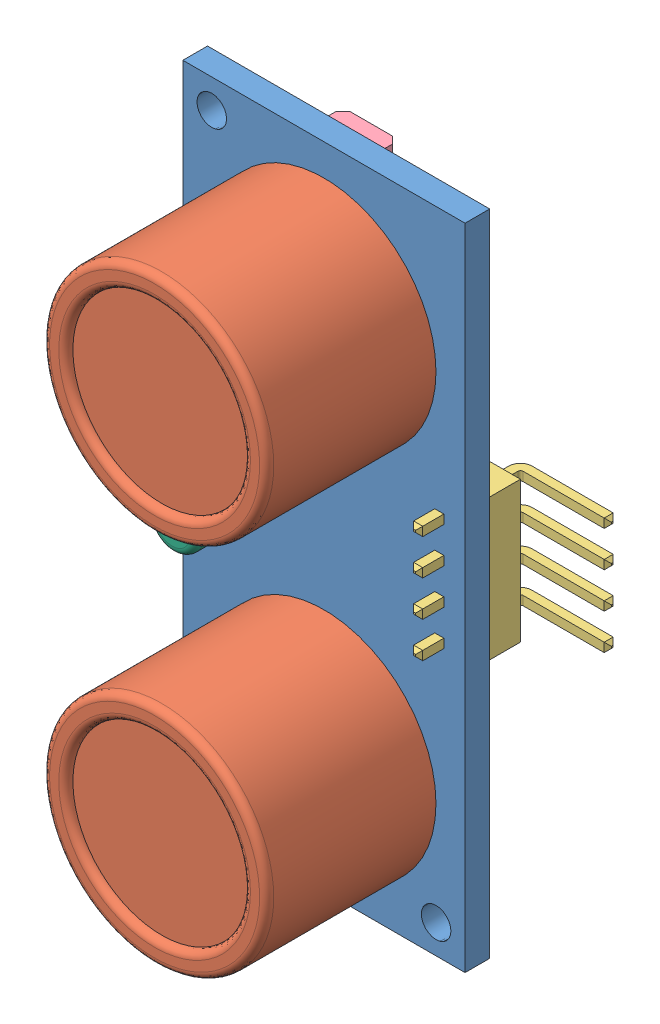
SolidWorks assembly HC-SR04 Ping Sensor, configuration Default. Lengths in mm.
Overall size (24.68 46 18.07).
14 component instances, 6 part files, 46 mates.
Components (placement in the parent):
- PCB-1: PCB [Default] at origin size (20 46 1.75)
- Transducer-1: Transducer [Default] at (0 -13.66 13.25) x (1 0 0) z (0 -1 0) size (15.88 12 15.88)
- Transducer-2: Transducer [Default] at (0 12.84 13.25) x (1 0 0) z (0 -1 0) size (15.88 12 15.88)
- 3 Pin Header 90 Degree-1: 3 Pin Header 90 Degree [Default] at (8.1775 0 -1.25) x (-1 0 0) z (0 -1 0) size (8 7.82 10)
- 14 Pin SMT-1: 14 Pin SMT [Default] at (-0.1 -19 -0.85) x (0 -1 0) z (1 0 0) size (6 1.6 8.8)
- 14 Pin SMT-2: 14 Pin SMT [Default] at (0 0.1174 -0.85) x (1 0 0) z (0 1 0) size (6 1.6 8.8)
- 14 Pin SMT-3: 14 Pin SMT [Default] at (0 18.0274 -0.85) x (1 0 0) z (0 1 0) size (6 1.6 8.8)
- Cap1 SMT-1: Cap1 SMT [Default] at (-1.505 7.9774 -0.9689) x (0 1 0) z (-1 0 0) size (4.5 1.84 1.75)
- Cap1 SMT-2: Cap1 SMT [Default] at (6.585 7.9774 -0.9689) x (0 1 0) z (-1 0 0) size (4.5 1.84 1.75)
- Cap1 SMT-3: Cap1 SMT [Default] at (-6.585 7.9774 -0.9689) x (0 1 0) z (-1 0 0) size (4.5 1.84 1.75)
- Cap1 SMT-4: Cap1 SMT [Default] at (4.045 7.9774 -0.9689) x (0 1 0) z (-1 0 0) size (4.5 1.84 1.75)
- Cap1 SMT-5: Cap1 SMT [Default] at (1.505 7.9774 -0.9689) x (0 1 0) z (-1 0 0) size (4.5 1.84 1.75)
- Cap1 SMT-6: Cap1 SMT [Default] at (-4.045 7.9774 -0.9689) x (0 1 0) z (-1 0 0) size (4.5 1.84 1.75)
- HC-SR04 Crystal-1: HC-SR04 Crystal [Default] at (-8.05 0 1.75) x (0 -1 0) z (0 0 1) size (10 3.5 2.7)
Mates (geometry in assembly coordinates):
- Coincident1: coincident anti-aligned: plane of PCB-1 through (-10 -23 1.75) normal (0 0 1); plane of Transducer-2 through (0 12.84 1.75) normal (0 0 -1)
- Coincident2: coincident anti-aligned: plane of PCB-1 through (-10 -23 1.75) normal (0 0 1); plane of Transducer-1 through (0 -13.66 1.75) normal (0 0 -1)
- Coincident3: coincident aligned: plane of PCB-1 through (0 0 0) normal (1 0 0); plane of Transducer-1
- Coincident4: coincident aligned: plane of PCB-1 through (0 0 0) normal (1 0 0); plane of Transducer-2
- Distance2: distance = 9.34 mm: plane of PCB-1 through (-10 -23 1.75) normal (0 -1 0); point of Transducer-1
- Distance3: distance = 10.16 mm: plane of PCB-1 through (-10 23 1.75) normal (0 1 0); point of Transducer-2
- Coincident8: coincident anti-aligned: plane of PCB-1 through (0 0 0) normal (0 1 0); plane of 3 Pin Header 90 Degree-1 through (8.1775 0 -1.25) normal (0 -1 0)
- Coincident9: coincident anti-aligned: plane of PCB-1 through (-10 -23 0) normal (0 0 -1); plane of 14 Pin SMT-1 through (-0.35 -22 0) normal (0 0 1)
- Coincident10: coincident anti-aligned: plane of PCB-1 through (-10 -23 0) normal (0 0 -1); plane of 14 Pin SMT-2 through (3 -0.1326 0) normal (0 0 1)
- Coincident11: coincident anti-aligned: plane of PCB-1 through (-10 -23 0) normal (0 0 -1); plane of 14 Pin SMT-3 through (3 19.0274 0) normal (0 0 1)
- Coincident13: coincident aligned: plane of PCB-1 through (0 0 0) normal (1 0 0); plane of 14 Pin SMT-2
- Coincident14: coincident aligned: plane of PCB-1 through (0 0 0) normal (1 0 0); plane of 14 Pin SMT-3
- Distance6: distance = 9.11 mm anti-aligned: plane of 14 Pin SMT-2 through (-2 4.5174 -1.6) normal (0 1 0); plane of 14 Pin SMT-3 through (-2 13.6274 -1.6) normal (0 -1 0)
- Coincident15: coincident anti-aligned: plane of PCB-1 through (-10 -23 0) normal (0 0 -1); plane of Cap1 SMT-1 through (-1.755 10.2274 0) normal (0 0 1)
- Coincident16: coincident anti-aligned: plane of PCB-1 through (-10 -23 0) normal (0 0 -1); plane of Cap1 SMT-2 through (6.335 10.2274 0) normal (0 0 1)
- Coincident17: coincident anti-aligned: plane of PCB-1 through (-10 -23 0) normal (0 0 -1); plane of Cap1 SMT-3 through (-6.835 10.2274 0) normal (0 0 1)
- Coincident18: coincident anti-aligned: plane of PCB-1 through (-10 -23 0) normal (0 0 -1); plane of Cap1 SMT-4 through (3.795 10.2274 0) normal (0 0 1)
- Coincident19: coincident anti-aligned: plane of PCB-1 through (-10 -23 0) normal (0 0 -1); plane of Cap1 SMT-5 through (1.255 10.2274 0) normal (0 0 1)
- Coincident20: coincident anti-aligned: plane of PCB-1 through (-10 -23 0) normal (0 0 -1); plane of Cap1 SMT-6 through (-4.295 10.2274 0) normal (0 0 1)
- Parallel1: parallel aligned: plane of Cap1 SMT-4 through (3.17 6.2274 -1.8439) normal (0 -1 0); plane of Cap1 SMT-5 through (0.63 6.2274 -1.8439) normal (0 -1 0)
- Parallel2: parallel aligned: plane of Cap1 SMT-2 through (5.71 6.2274 -1.8439) normal (0 -1 0); plane of Cap1 SMT-4 through (3.17 6.2274 -1.8439) normal (0 -1 0)
- Parallel3: parallel aligned: plane of PCB-1 through (-10 -23 1.75) normal (0 -1 0); plane of Cap1 SMT-2 through (5.71 6.2274 -1.8439) normal (0 -1 0)
- Distance7: distance = 0.79 mm anti-aligned: plane of Cap1 SMT-2 through (5.71 6.2274 -1.8439) normal (-1 0 0); plane of Cap1 SMT-4 through (4.92 6.2274 -1.8439) normal (1 0 0)
- Distance8: distance = 0.79 mm anti-aligned: plane of Cap1 SMT-4 through (3.17 6.2274 -1.8439) normal (-1 0 0); plane of Cap1 SMT-5 through (2.38 6.2274 -1.8439) normal (1 0 0)
- Distance9: distance = 2.54 mm aligned: plane of PCB-1 through (10 23 1.75) normal (1 0 0); plane of Cap1 SMT-2 through (7.46 6.2274 -1.8439) normal (1 0 0)
- Coincident21: coincident aligned: plane of Cap1 SMT-4 through (3.17 9.7274 -0.0939) normal (0 1 0); plane of Cap1 SMT-5 through (0.63 9.7274 -0.0939) normal (0 1 0)
- Coincident22: coincident aligned: plane of Cap1 SMT-2 through (5.71 9.7274 -0.0939) normal (0 1 0); plane of Cap1 SMT-4 through (3.17 9.7274 -0.0939) normal (0 1 0)
- Parallel4: parallel aligned: plane of Cap1 SMT-3 through (-7.46 6.2274 -1.8439) normal (0 -1 0); plane of Cap1 SMT-6 through (-4.92 6.2274 -1.8439) normal (0 -1 0)
- Parallel5: parallel aligned: plane of Cap1 SMT-1 through (-2.38 6.2274 -1.8439) normal (0 -1 0); plane of Cap1 SMT-6 through (-4.92 6.2274 -1.8439) normal (0 -1 0)
- Distance11: distance = 0.79 mm anti-aligned: plane of Cap1 SMT-1 through (-2.38 6.2274 -1.8439) normal (-1 0 0); plane of Cap1 SMT-6 through (-3.17 6.2274 -1.8439) normal (1 0 0)
- Distance12: distance = 0.79 mm anti-aligned: plane of Cap1 SMT-3 through (-5.71 6.2274 -1.8439) normal (1 0 0); plane of Cap1 SMT-6 through (-4.92 6.2274 -1.8439) normal (-1 0 0)
- Coincident23: coincident aligned: plane of Cap1 SMT-3 through (-7.46 9.7274 -0.0939) normal (0 1 0); plane of Cap1 SMT-6 through (-4.92 9.7274 -0.0939) normal (0 1 0)
- Coincident24: coincident aligned: plane of Cap1 SMT-1 through (-2.38 9.7274 -0.0939) normal (0 1 0); plane of Cap1 SMT-6 through (-4.92 9.7274 -0.0939) normal (0 1 0)
- Parallel6: parallel aligned: plane of PCB-1 through (-10 -23 1.75) normal (0 -1 0); plane of Cap1 SMT-3 through (-7.46 6.2274 -1.8439) normal (0 -1 0)
- Distance13: distance = 2.54 mm aligned: plane of PCB-1 through (-10 23 1.75) normal (-1 0 0); plane of Cap1 SMT-3 through (-7.46 6.2274 -1.8439) normal (-1 0 0)
- Coincident25: coincident aligned: plane of Cap1 SMT-1 through (-2.38 9.7274 -0.0939) normal (0 1 0); plane of Cap1 SMT-5 through (0.63 9.7274 -0.0939) normal (0 1 0)
- Distance15: distance = 1.71 mm anti-aligned: plane of 14 Pin SMT-2 through (-2 4.5174 -1.6) normal (0 1 0); plane of Cap1 SMT-5 through (0.63 6.2274 -1.8439) normal (0 -1 0)
- Coincident26: coincident anti-aligned: plane of PCB-1 through (-10 -23 0) normal (0 0 -1); plane of 3 Pin Header 90 Degree-1 through (9.6775 -5 0) normal (0 0 1)
- Distance16: distance = 1.5 mm aligned: plane of 3 Pin Header 90 Degree-1 through (8.5 4.4 -2.5) normal (1 0 0); plane of PCB-1 through (10 23 1.75) normal (1 0 0)
- Parallel7: parallel anti-aligned: plane of PCB-1 through (-10 23 1.75) normal (-1 0 0); plane of 14 Pin SMT-1 through (4.3 -17 -1.6) normal (1 0 0)
- Distance17: distance = 5.5 mm aligned: plane of 14 Pin SMT-1 through (-4.5 -17 -1.6) normal (-1 0 0); plane of PCB-1 through (-10 23 1.75) normal (-1 0 0)
- Distance18: distance = 2 mm aligned: plane of 14 Pin SMT-1 through (4.3 -21 -0.1) normal (0 -1 0); plane of PCB-1 through (-10 -23 1.75) normal (0 -1 0)
- Distance19: distance = 0.5726 mm aligned: plane of 14 Pin SMT-3 through (-2 22.4274 -1.6) normal (0 1 0); plane of PCB-1 through (-10 23 1.75) normal (0 1 0)
- Distance20: distance = 0.2 mm aligned: plane of PCB-1 through (-10 23 1.75) normal (-1 0 0); plane of HC-SR04 Crystal-1 through (-9.8 3.25 4.45) normal (-1 0 0)
- Coincident36: coincident anti-aligned: plane of PCB-1 through (-10 -23 1.75) normal (0 0 1); plane of HC-SR04 Crystal-1 through (-8.05 3.25 1.75) normal (0 0 -1)
- Coincident37: coincident anti-aligned: plane of HC-SR04 Crystal-1; plane of assembly through (0 0 0) normal (0 1 0)
